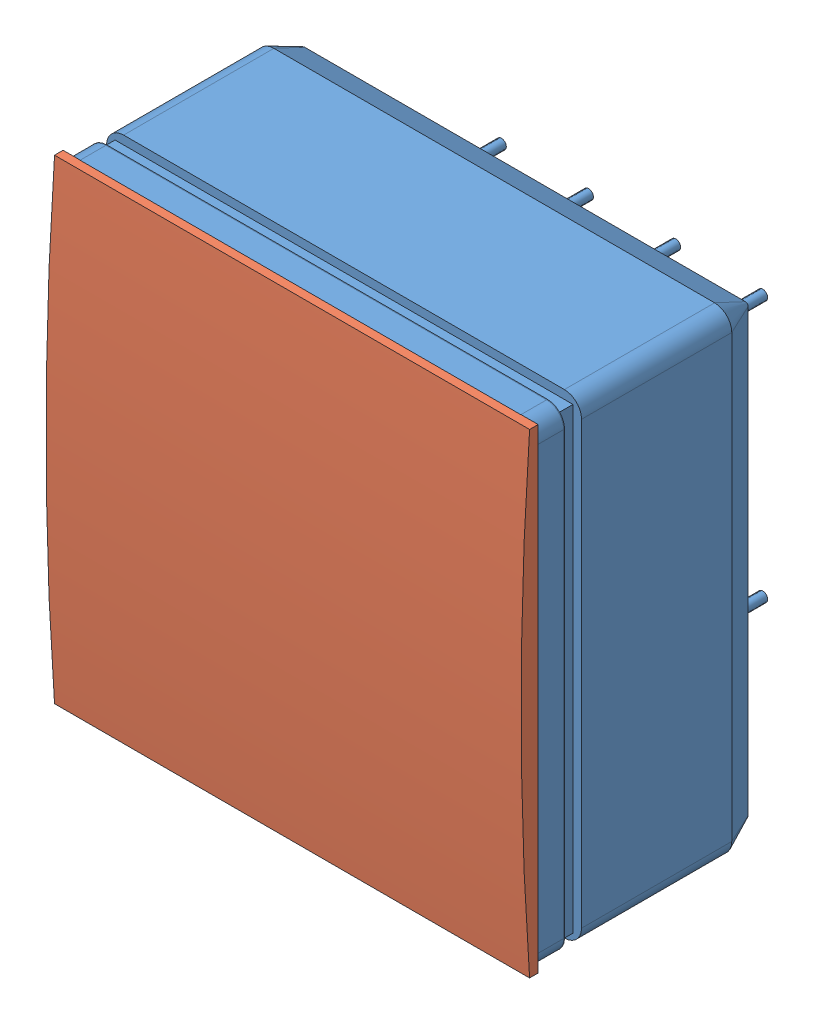
SolidWorks assembly PMT-with-cookie, configuration Default. Lengths in mm.
Overall size (27.7 27.7 17.79).
3 component instances, 3 part files, 0 mates.
Components (placement in the parent):
- SL10.4x4-1: SL10.4x4 [Default] at origin size (27.7 27.7 16.8)
- cookie-1: cookie [Default] at (0 0 -2.5103) size (27.7 27.7 1)
- filter-1: filter [Default] at (0 0 0.4946) (suppressed, hidden)
